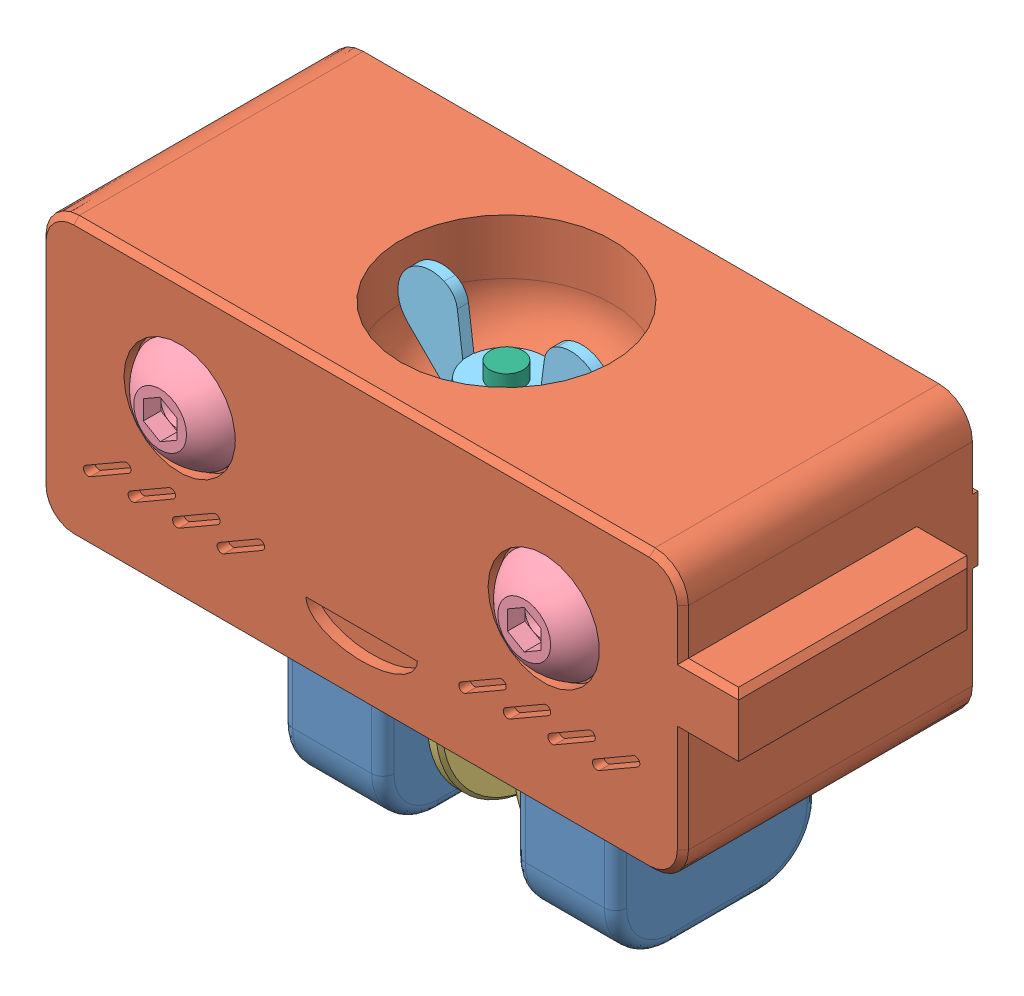
SolidWorks assembly Flush_Assembly, configuration 默认. Lengths in mm.
Overall size (62.7 42.6 32.75).
8 component instances, 6 part files, 16 mates.
Components (placement in the parent):
- z_belt_tensioner_flush-1: z_belt_tensioner_flush [默认] at (-5.5054 -0.6783 40.1) size (48 41 18.58)
- z_belt_holder_flush-1: z_belt_holder_flush [默认] at (-5.5054 6.1217 32.9) size (62.7 25 27)
- GT2 20T Idler-1: GT2 20T Idler [默认] at (-16.7054 -17.4783 39.7) size (8.6 18 18)
- M5x30 BHCS-1: M5x30 BHCS [默认] at (-21.8554 6.1217 60.65) x (0 0 -1) z (1 0 0) size (32.75 9.5 9.5)
- M5x30 BHCS-2: M5x30 BHCS [默认] at (-23.2554 -17.4783 39.7) x (1 0 0) z (0 -0.575292 0.817948) size (32.75 9.5 9.5)
- M5x30 BHCS-3: M5x30 BHCS [默认] at (10.8446 6.1217 60.65) x (0 0 -1) z (1 0 0) size (32.75 9.5 9.5)
- Wings Nut-1: Wings Nut [默认] at (-5.5054 6.1217 45.9) size (18.5 9.5 7.9)
- M3x16 HHCS-1: M3x16 HHCS [默认] at (-5.5054 -4.4783 45.9) x (1 0 0) z (0 0 -1) size (6.35 18.64 5.5)
Mates (geometry in assembly coordinates):
- 同心1: concentric anti-aligned: cylinder of z_belt_tensioner_flush-1 through (18.4946 -17.4783 39.7) axis (-1 0 0) radius 2.776; cylinder of GT2 20T Idler-1 through (-9.8054 -17.4783 39.7) axis (1 0 0) radius 2.5
- 距离1: distance = 1.6 mm anti-aligned: plane of z_belt_tensioner_flush-1 through (0.3946 -0.6783 32.9) normal (-1 0 0); plane of GT2 20T Idler-1 through (-1.2054 -17.4783 39.7) normal (1 0 0)
- 同心2: concentric aligned: cylinder of z_belt_tensioner_flush-1 through (18.4946 -17.4783 39.7) axis (-1 0 0) radius 2.776; cylinder of M5x30 BHCS-2 through (-23.2554 -17.4783 39.7) axis (-1 0 0) radius 2.5
- 重合4: coincident anti-aligned: plane of z_belt_tensioner_flush-1 through (18.4946 -21.4783 37.9) normal (1 0 0); plane of z_belt_holder_flush-1 through (18.4946 6.1217 32.9) normal (-1 0 0)
- 平行2: parallel anti-aligned: plane of z_belt_tensioner_flush-1 through (18.4946 -0.6783 40.1) normal (0 1 0); plane of z_belt_holder_flush-1 through (18.4946 -0.6783 40.1) normal (0 -1 0)
- 重合6: coincident anti-aligned: plane of z_belt_tensioner_flush-1 through (18.4946 -0.6783 40.1) normal (0 1 0); plane of z_belt_holder_flush-1 through (18.4946 -0.6783 40.1) normal (0 -1 0)
- 同心3: concentric anti-aligned: cylinder of z_belt_tensioner_flush-1 through (10.8446 6.1217 32.9) axis (0 0 1) radius 2.7; cylinder of z_belt_holder_flush-1 through (10.8446 6.1217 58.9) axis (0 0 -1) radius 2.7
- 同心4: concentric anti-aligned: cylinder of z_belt_holder_flush-1 through (10.8446 6.1217 58.9) axis (0 0 -1) radius 2.7; cylinder of M5x30 BHCS-3 through (10.8446 6.1217 60.65) axis (0 0 1) radius 2.5
- 重合7: coincident anti-aligned: plane of z_belt_holder_flush-1 through (10.8446 6.1217 57.9) normal (0 0 1); plane of M5x30 BHCS-3 through (10.8446 8.6217 57.9) normal (0 0 -1)
- 同心5: concentric anti-aligned: cylinder of z_belt_holder_flush-1 through (-21.8554 6.1217 58.9) axis (0 0 -1) radius 2.7; cylinder of M5x30 BHCS-1 through (-21.8554 6.1217 60.65) axis (0 0 1) radius 2.5
- 重合8: coincident anti-aligned: plane of z_belt_holder_flush-1 through (-21.8554 6.1217 57.9) normal (0 0 1); plane of M5x30 BHCS-1 through (-21.8554 8.6217 57.9) normal (0 0 -1)
- 同心6: concentric anti-aligned: cylinder of z_belt_holder_flush-1 through (-5.5054 16.1217 45.9) axis (0 1 0) radius 1.6; cylinder of M3x16 HHCS-1 through (-5.5054 11.5217 45.9) axis (0 -1 0) radius 1.5
- 重合9: coincident anti-aligned: plane of z_belt_tensioner_flush-1 through (-5.5054 -4.4783 40.1) normal (0 -1 0); plane of M3x16 HHCS-1 through (-5.5054 -4.4783 45.9) normal (0 1 0)
- 重合10: coincident anti-aligned: plane of z_belt_tensioner_flush-1 through (-3.9177 -4.4783 48.65) normal (0 0 -1); plane of M3x16 HHCS-1 through (-3.9177 -6.6783 48.65) normal (0 0 1)
- 同心7: concentric aligned: cylinder of Wings Nut-1 through (-5.5054 10.1217 45.9) axis (0 -1 0) radius 1.5; cylinder of M3x16 HHCS-1 through (-5.5054 11.5217 45.9) axis (0 -1 0) radius 1.5
- 重合11: coincident anti-aligned: plane of z_belt_holder_flush-1 through (-5.5054 6.1217 44.3) normal (0 1 0); plane of Wings Nut-1 through (-5.5054 6.1217 45.9) normal (0 -1 0)
